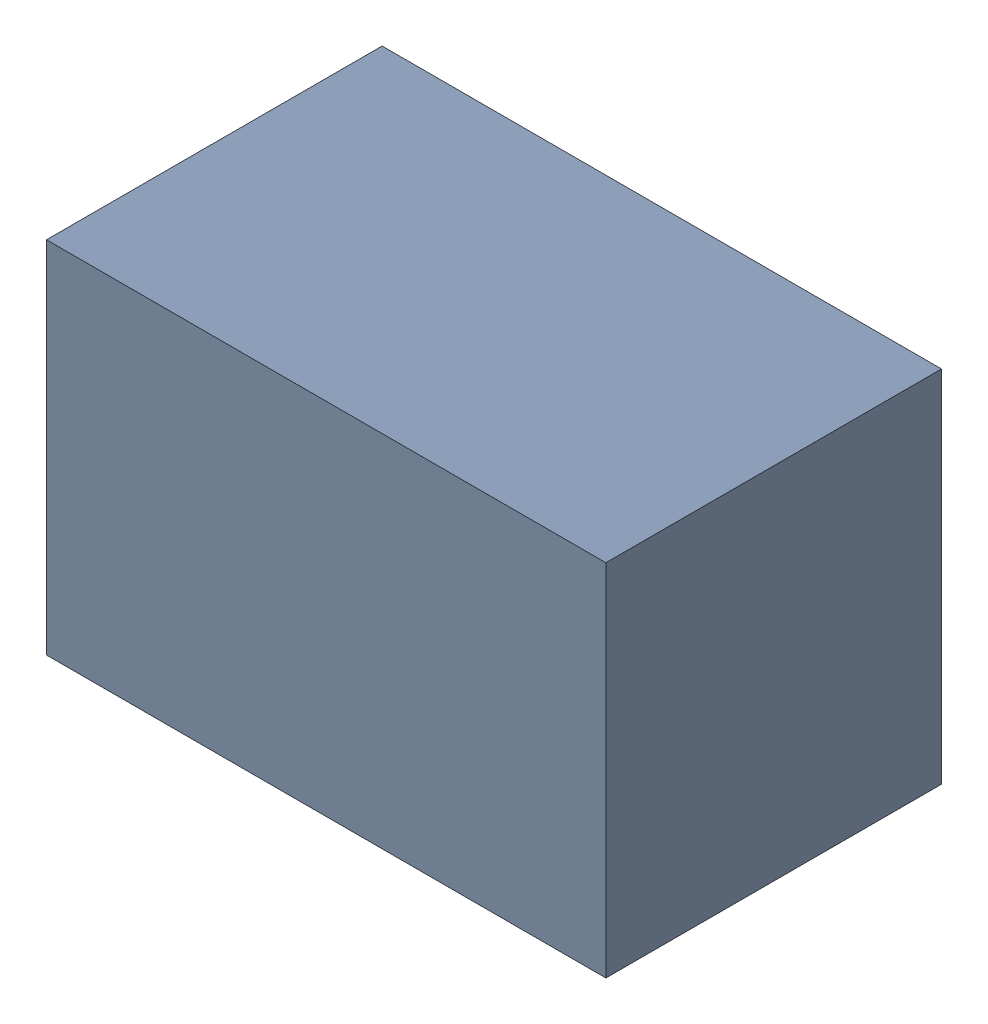
SolidWorks assembly C33, configuration Default. Lengths in mm.
Overall size (2.1 1.35 1.26).
2 component instances, 1 part files, 0 mates.
Components (placement in the parent):
- 407985824-1: 407985824 [Default] at (60.071 24.384 0.0127) size (2.1 1.35 1.26)
  - Extruded_2-1: Extruded_2 [Default] at origin size (2.1 1.35 1.26)
